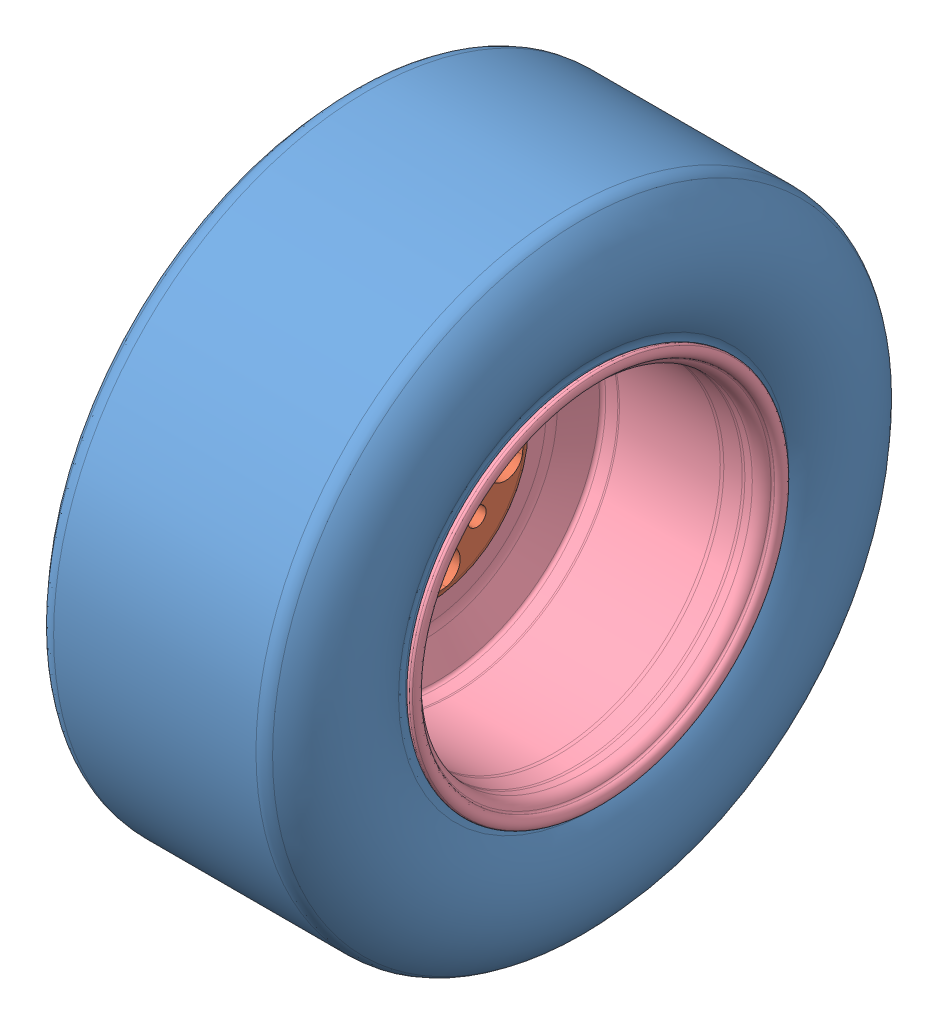
SolidWorks assembly FS2-WT-A-0001-V1, FRONT TIRE, configuration Default. Lengths in mm.
Overall size (205.74 459.74 459.74).
4 component instances, 4 part files, 7 mates.
Components (placement in the parent):
- TYRE, 18.0X 6.0-10 R25B C2000, H43101R25B, Hoozier-1: TYRE, 18.0X 6.0-10 R25B C2000, H43101R25B, Hoozier [7] at origin size (205.74 459.74 459.74)
- WHEEL, 10i Center, Keizer-1: WHEEL, 10i Center, Keizer [Default] at (-49.403 0 0) x (0 0 1) z (-1 0 0) size (187.33 187.33 20.83)
- WHEEL, OUTER HALF 10x2 10i, Keizer-1: WHEEL, OUTER HALF 10x2 10i, Keizer [Default] at (-38.608 0 0) x (0 0 1) z (-1 0 0) size (276.85 276.85 58.63)
- WHEEL, INNER HALF 10x5BC 10i, Keizer-2: WHEEL, INNER HALF 10x5BC 10i, Keizer [Default] at (-38.608 0 0) x (0 0 -1) z (1 0 0) size (276.85 276.85 137.37)
Mates (geometry in assembly coordinates):
- Coincident2: coincident: point of TYRE, 18.0X 6.0-10 R25B C2000, H43101R25B, Hoozier-1
- Coincident3: coincident anti-aligned: plane of TYRE, 18.0X 6.0-10 R25B C2000, H43101R25B, Hoozier-1 through (-88.9 0 0) normal (-1 0 0); circle of WHEEL, OUTER HALF 10x2 10i, Keizer-1
- Concentric1: concentric aligned: cylinder of TYRE, 18.0X 6.0-10 R25B C2000, H43101R25B, Hoozier-1 through (0 0 0) axis (1 0 0) radius 229.87; cone of WHEEL, OUTER HALF 10x2 10i, Keizer-1 through (-70.3228 0 0) axis (1 0 0)
- Coincident4: coincident anti-aligned: plane of WHEEL, 10i Center, Keizer-1 through (-41.783 -94.7864 -94.7864) normal (1 0 0); plane of WHEEL, OUTER HALF 10x2 10i, Keizer-1 through (-41.783 0 0) normal (-1 0 0)
- Concentric2: concentric anti-aligned: cylinder of TYRE, 18.0X 6.0-10 R25B C2000, H43101R25B, Hoozier-1 through (0 0 0) axis (1 0 0) radius 229.87; cylinder of WHEEL, 10i Center, Keizer-1 through (-41.783 0 0) axis (-1 0 0) radius 93.6625
- Coincident7: coincident anti-aligned: plane of WHEEL, OUTER HALF 10x2 10i, Keizer-1 through (-38.608 0 0) normal (1 0 0); plane of WHEEL, INNER HALF 10x5BC 10i, Keizer-2 through (-38.608 0 0) normal (-1 0 0)
- Concentric5: concentric aligned: cylinder of WHEEL, 10i Center, Keizer-1 through (-34.7504 0 0) axis (-1 0 0) radius 75.8825; cylinder of WHEEL, INNER HALF 10x5BC 10i, Keizer-2 through (98.7662 0 0) axis (-1 0 0) radius 76.2
